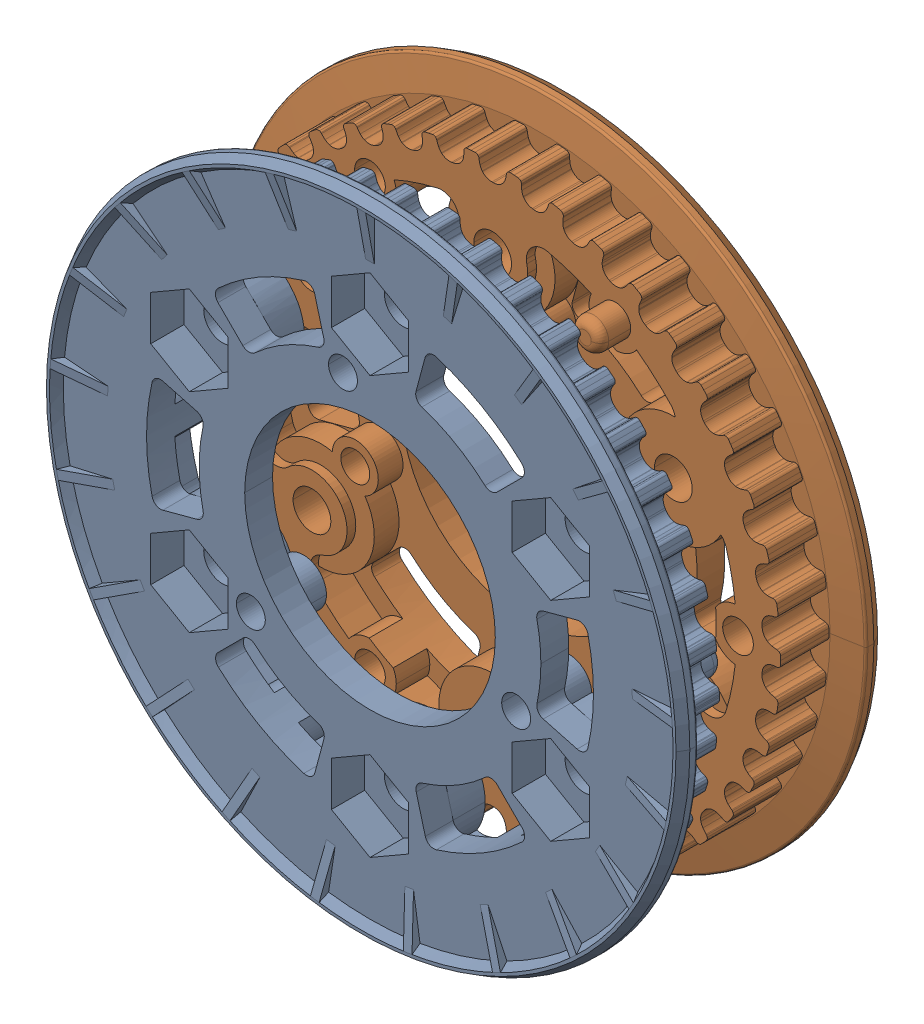
SolidWorks assembly 42t_x_18mm_Wide_VersaPulley_Kit_HTD_5mm_VersaKeys_217-3199(2), configuration Default. Lengths in mm.
Overall size (73 73 23).
2 component instances, 2 part files, 0 mates.
Components (placement in the parent):
- 42tVersaPulleyOuter-1: 42tVersaPulleyOuter [Default] at origin size (73 73 11.5)
- 217-3199-001 Rev4-2: 217-3199-001 Rev4 [Default] at (0 0 -17.825) x (-1 0 0) z (0 0 -1) size (73 73 11.5)
